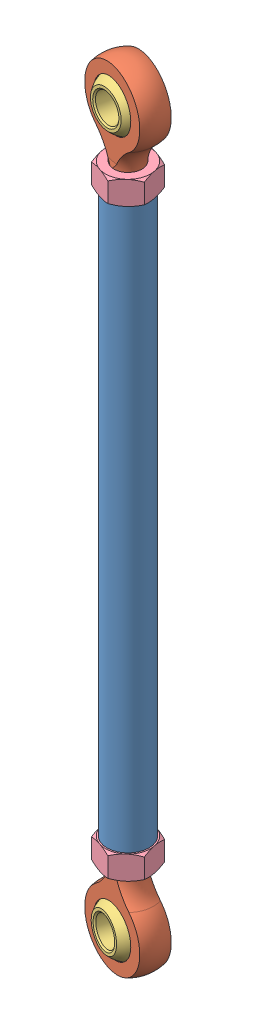
SolidWorks assembly TieRodMock, configuration Default. Lengths in mm.
Overall size (30.3 281.9 21.04).
9 component instances, 4 part files, 4 mates.
Components (placement in the parent):
- RodBody-1: RodBody [Default] at origin size (15 200 15)
- SphericalRodEnd M10x1.5-1: SphericalRodEnd M10x1.5 [Default] at (0 127.4 0) x (0.97913 0 0.203236) z (-0.203236 0 0.97913) size (27.69 61.55 15.68) (flexible)
  - BallJointEndRodPt1-1: BallJointEndRodPt1 [Default] at origin size (27 61.5 11)
  - BallJointEndRodPt2-1: BallJointEndRodPt2 [Default] x (-0.651341 -0.756905 0.053385) z (0.062472 0.016624 0.997908) size (19.05 19.05 14)
- hex nut style 1_am-1: hex nut style 1_am [B18.2.4.1M - Hex nut, Style 1,  M10 x 1.5, with 16mm WAF --D-N] at (0 108.4 0) x (0.317758 0 -0.948172) z (0 1 0) size (16 18.48 8.4)
- hex nut style 1_am-3: hex nut style 1_am [B18.2.4.1M - Hex nut, Style 1,  M10 x 1.5, with 16mm WAF --D-N] at (0 -100 0) x (0.317758 0 -0.948172) z (0 1 0) size (16 18.48 8.4)
- SphericalRodEnd M10x1.5-3: SphericalRodEnd M10x1.5 [Default] at (0 -127.4 0) x (0.97913 0 0.203236) z (0.203236 0 -0.97913) size (27 61.5 14.26) (flexible)
  - BallJointEndRodPt1-1: BallJointEndRodPt1 [Default] at origin size (27 61.5 11)
  - BallJointEndRodPt2-1: BallJointEndRodPt2 [Default] x (-0.651341 -0.756905 0.053385) z (0.062472 0.016624 0.997908) size (19.05 19.05 14)
Mates (geometry in assembly coordinates):
- Screw2: screw = 1 anti-aligned: cylinder of RodBody-1 through (0 100 0) axis (0 -1 0) radius 5; cylinder of SphericalRodEnd M10x1.5-1/BallJointEndRodPt1-1 through (0 127.4 0) axis (0 1 0) radius 5
- Concentric1: concentric anti-aligned: cylinder of RodBody-1 through (0 100 0) axis (0 -1 0) radius 5; cylinder of hex nut style 1_am-1 through (0 83.3625 0) axis (0 1 0) radius 5
- Coincident1: coincident anti-aligned: plane of RodBody-1 through (0 100 0) normal (0 1 0); plane of hex nut style 1_am-1 through (-8.7588 100 -2.9353) normal (0 -1 0)
- Coincident2: coincident anti-aligned: circle of SphericalRodEnd M10x1.5-1/BallJointEndRodPt1-1; plane of hex nut style 1_am-1 through (-8.7588 108.4 -2.9353) normal (0 1 0)
